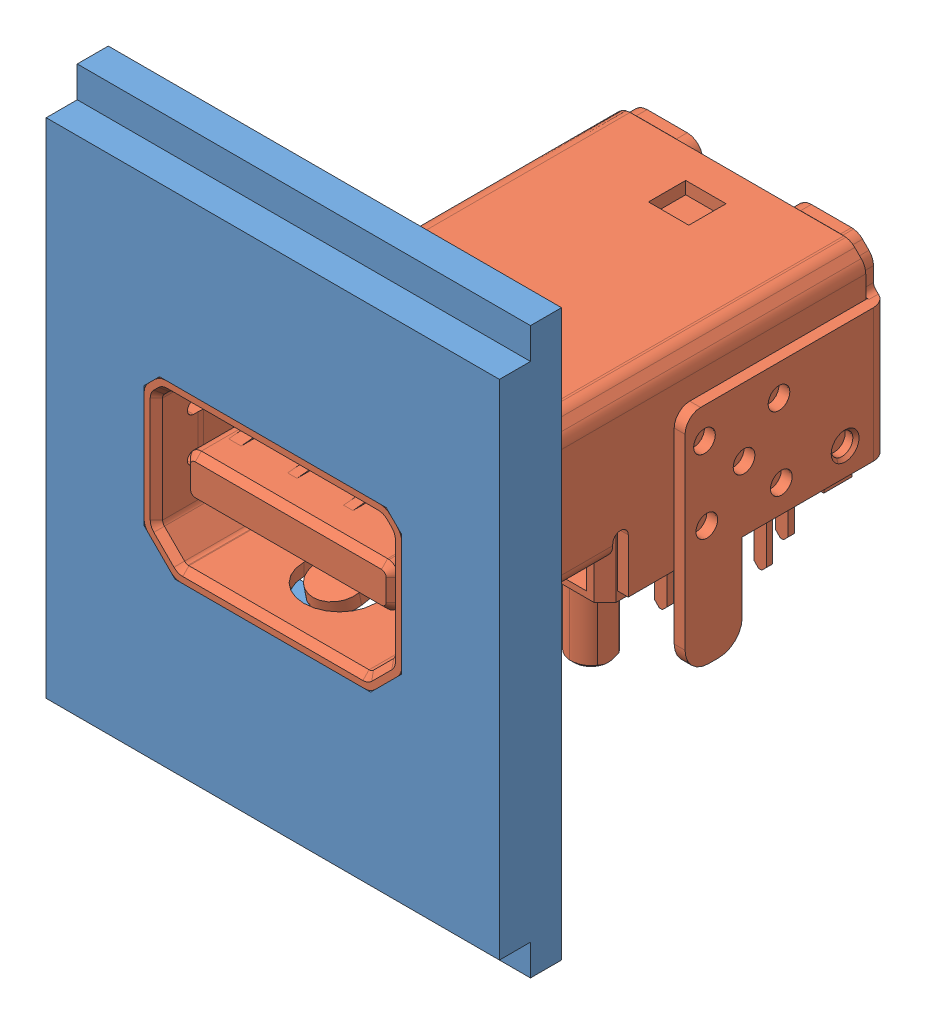
SolidWorks assembly Keystone-miniDisplayport, configuration Standard. Lengths in mm.
Overall size (14.6 21.06 21.87).
2 component instances, 2 part files, 6 mates.
Components (placement in the parent):
- Keystone-MDisp-Pannel-1: Keystone-MDisp-Pannel [Standard] at (-14.6 -17.2 0) x (-1 0 0) z (0 0 -1) size (14.6 18.2 2)
- Mini Displayport Molex-sd-105081-001-1: Mini Displayport Molex-sd-105081-001 [Standard] at (-3.4696 -12.9949 -3.752) x (0.156434 0.855363 -0.493844) z (0 0.5 0.866025) size (13.15 10.33 16.82)
Mates (geometry in assembly coordinates):
- Deckungsgleich1: coincident aligned: plane of Keystone-MDisp-Pannel-1 through (-14.6 -17.2 0) normal (0 0 1); plane of assembly through (0 0 0) normal (0 0 1)
- Deckungsgleich2: coincident aligned: plane of Keystone-MDisp-Pannel-1 through (0 -17.2 -1) normal (1 0 0); plane of assembly through (0 0 0) normal (1 0 0)
- Deckungsgleich3: coincident aligned: plane of Keystone-MDisp-Pannel-1 through (0 0 -2) normal (0 1 0); plane of assembly through (0 0 0) normal (0 1 0)
- Deckungsgleich4: coincident: plane of Keystone-MDisp-Pannel-1 through (-3.65 -6.4 -10) normal (0 -1 0); plane of Mini Displayport Molex-sd-105081-001-1 through (-7.3 -6.4 -7.675) normal (0 1 0)
- Deckungsgleich5: coincident: plane of Keystone-MDisp-Pannel-1 through (-14.6 -17.2 0) normal (0 0 1); plane of Mini Displayport Molex-sd-105081-001-1 through (-3.15 -11.8 0) normal (0 0 1)
- Deckungsgleich6: coincident anti-aligned: plane of Keystone-MDisp-Pannel-1 through (-3.15 -6.9 -10) normal (-1 0 0); plane of Mini Displayport Molex-sd-105081-001-1 through (-3.15 -11.8 -15.35) normal (1 0 0)
